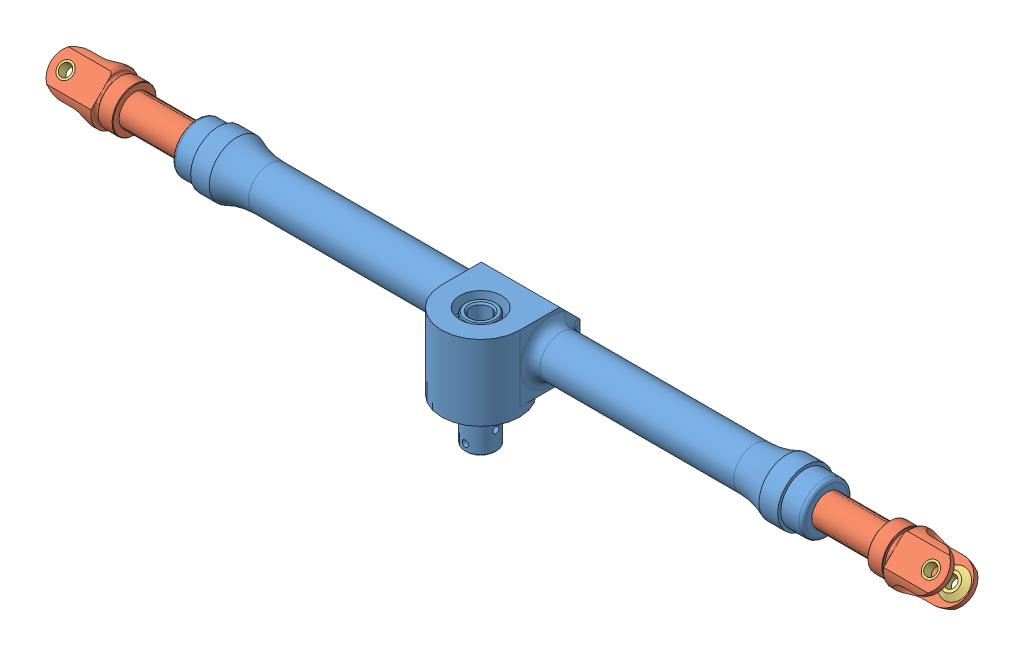
SolidWorks assembly PUTM-S-SS-SS-Rack_and_pinion, configuration Domyślna. Lengths in mm.
Overall size (459.34 60.02 52.94).
6 component instances, 3 part files, 4 mates.
Components (placement in the parent):
- PUTM-S-SS-SS-Pinion-1: PUTM-S-SS-SS-Pinion [Domyślna] at (-13.4847 -7.9013 -9.0673) size (322.08 60.02 50.73)
- PUTM-S-SS-SS-Rack-1: PUTM-S-SS-SS-Rack [Domyślna] at (-13.4797 9.1187 -19.7023) x (0 -0.704375 0.709828) z (0 0.709828 0.704375) size (25.4 457.21 22.5)
- PUTM-S-SS-SS-Mush-1: PUTM-S-SS-SS-Mush [Domyślna] at (207.5103 5.9244 -22.872) x (-0.966337 -0.181222 0.182625) z (0.257281 -0.680663 0.685933) size (14.19 5.5 14.19)
- PUTM-S-SS-SS-Mush-2: PUTM-S-SS-SS-Mush [Domyślna] at (207.5103 12.3129 -16.5326) x (-0.966337 -0.181222 0.182625) z (-0.257281 0.680663 -0.685933) size (14.19 5.5 14.19)
- PUTM-S-SS-SS-Mush-3: PUTM-S-SS-SS-Mush [Domyślna] at (-234.4697 5.9244 -22.872) x (0.966337 -0.181222 0.182625) z (0.257281 0.680663 -0.685933) size (14.19 5.5 14.19)
- PUTM-S-SS-SS-Mush-4: PUTM-S-SS-SS-Mush [Domyślna] at (-234.4697 12.3129 -16.5326) x (0.966337 -0.181222 0.182625) z (-0.257281 -0.680663 0.685933) size (14.19 5.5 14.19)
Mates (geometry in assembly coordinates):
- Koncentryczne1: concentric anti-aligned: circle of PUTM-S-SS-SS-Pinion-1; circle of PUTM-S-SS-SS-Rack-1
- Odległość1: distance = 31.75 mm anti-aligned: plane of PUTM-S-SS-SS-Pinion-1 through (147.5553 9.1187 -19.7023) normal (1 0 0); plane of PUTM-S-SS-SS-Rack-1 through (179.3053 9.1187 -19.7023) normal (-1 0 0)
- Koncentryczne2: concentric anti-aligned: cylinder of PUTM-S-SS-SS-Rack-1 through (207.5103 16.2098 -12.6656) axis (0 0.709828 0.704375) radius 3.175; cylinder of PUTM-S-SS-SS-Mush-1 through (207.5103 2.0239 -26.7425) axis (0 -0.709828 -0.704375) radius 3
- Wspólnie1: coincident anti-aligned: plane of PUTM-S-SS-SS-Rack-1 through (-13.4797 12.9925 -33.7498) normal (0 0.709828 0.704375); plane of PUTM-S-SS-SS-Mush-1 through (203.645 3.322 -24.0045) normal (0 -0.709828 -0.704375)
